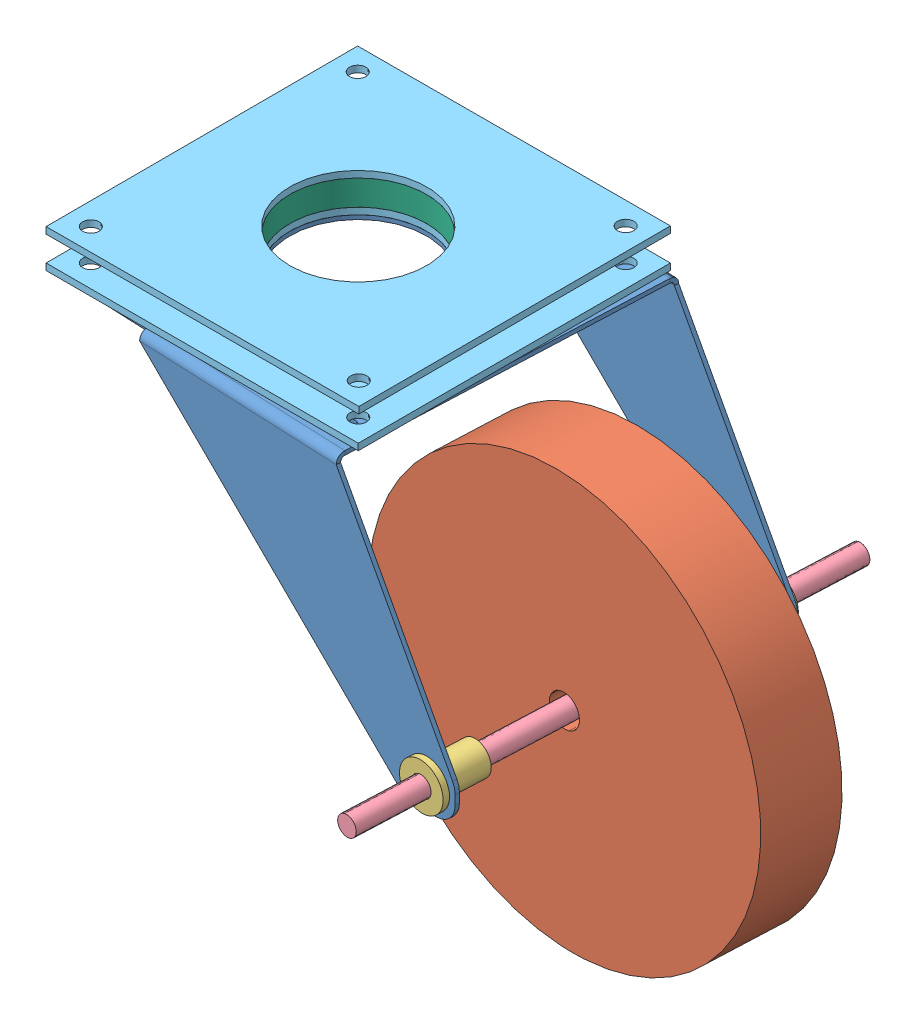
SolidWorks assembly actual caster assembly, configuration Default. Lengths in mm.
Overall size (153.41 118.4 120.09).
9 component instances, 6 part files, 11 mates.
Components (placement in the parent):
- actual caster support-2: actual caster support [Default] at (-16.3285 106.3 0.1571) x (0.999071 0 0.043084) z (-0.043084 0 0.999071) size (106.3 63 80)
- caster wheel 100mm with bushing hole offset-2: caster wheel 100mm with bushing hole offset [Default] at (45.3856 49.3 -8.1258) x (0.998194 0.041908 0.043046) z (0.041869 -0.999121 0.001806) size (100 19 100)
- bushing-4: bushing [Default] at (45.3856 49.3 -8.1258) x (0.999071 0 0.043084) z (-0.043084 0 0.999071) size (11.1 11.1 12.7)
- bushing-5: bushing [Default] at (43.1912 49.3 42.761) x (-0.985259 0.165712 -0.042488) z (0.043084 0 -0.999071) size (11.1 11.1 12.7)
- bushing-6: bushing [Default] at (46.6379 49.3 -37.1647) x (0.999071 0 0.043084) z (-0.043084 0 0.999071) size (11.1 11.1 12.7)
- rear wheel axel-2: rear wheel axel [Default] at (47.5481 49.3 -58.2719) x (0.999071 0 0.043084) z (-0.043084 0 0.999071) size (4.75 4.75 120)
- small lazy susan top and bottom-1: small lazy susan top and bottom [Default] at (-16.3285 107.9 0.1571) size (76 1.6 76)
- small lazy susan top and bottom-2: small lazy susan top and bottom [Default] at (-16.3285 115.65 0.1571) x (0.999998 0 -0.001925) z (0.001925 0 0.999998) size (76 1.6 76)
- small lazy susan bearing mockup-1: small lazy susan bearing mockup [Default] at (-16.3285 107.9 0.1571) size (53.3 6.15 53.3)
Mates (geometry in assembly coordinates):
- Coincident9: coincident anti-aligned: plane of actual caster support-2 through (-14.6052 106.3 -39.8057) normal (0.043084 0 -0.999071); plane of bushing-6 through (46.6379 49.3 -37.1647) normal (-0.043084 0 0.999071)
- Concentric1: concentric anti-aligned: circle of actual caster support-2; cylinder of bushing-6 through (46.1554 49.3 -25.9751) axis (0.043084 0 -0.999071) radius 3.975
- Coincident11: coincident anti-aligned: plane of actual caster support-2 through (-18.0519 106.3 40.12) normal (-0.043084 0 0.999071); plane of bushing-5 through (43.1912 49.3 42.761) normal (0.043084 0 -0.999071)
- Concentric2: concentric aligned: cylinder of actual caster support-2 through (43.6221 49.3 32.7703) axis (-0.043084 0 0.999071) radius 4; cylinder of bushing-5 through (43.6738 49.3 31.5714) axis (-0.043084 0 0.999071) radius 3.975
- Concentric3: concentric aligned: cylinder of bushing-6 through (46.1554 49.3 -25.9751) axis (0.043084 0 -0.999071) radius 2.475; cylinder of rear wheel axel-2 through (42.3781 49.3 61.6167) axis (0.043084 0 -0.999071) radius 2.375
- Concentric4: concentric anti-aligned: cylinder of caster wheel 100mm with bushing hole offset-2 through (45.3856 49.3 -8.1258) axis (-0.043084 0 0.999071) radius 3.85; cylinder of bushing-4 through (44.9031 49.3 3.0638) axis (0.043084 0 -0.999071) radius 3.975
- Coincident12: coincident anti-aligned: plane of caster wheel 100mm with bushing hole offset-2 through (45.3856 49.3 -8.1258) normal (0.043084 0 -0.999071); plane of bushing-4 through (45.3856 49.3 -8.1258) normal (-0.043084 0 0.999071)
- Concentric5: concentric aligned: cylinder of bushing-4 through (44.9031 49.3 3.0638) axis (0.043084 0 -0.999071) radius 2.475; cylinder of rear wheel axel-2 through (42.3781 49.3 61.6167) axis (0.043084 0 -0.999071) radius 2.375
- Coincident15: coincident aligned: circle of actual caster support-2; circle of small lazy susan top and bottom-1
- Coincident16: coincident aligned: circle of small lazy susan top and bottom-1; circle of small lazy susan bearing mockup-1
- Coincident17: coincident aligned: circle of small lazy susan top and bottom-2; circle of small lazy susan bearing mockup-1
